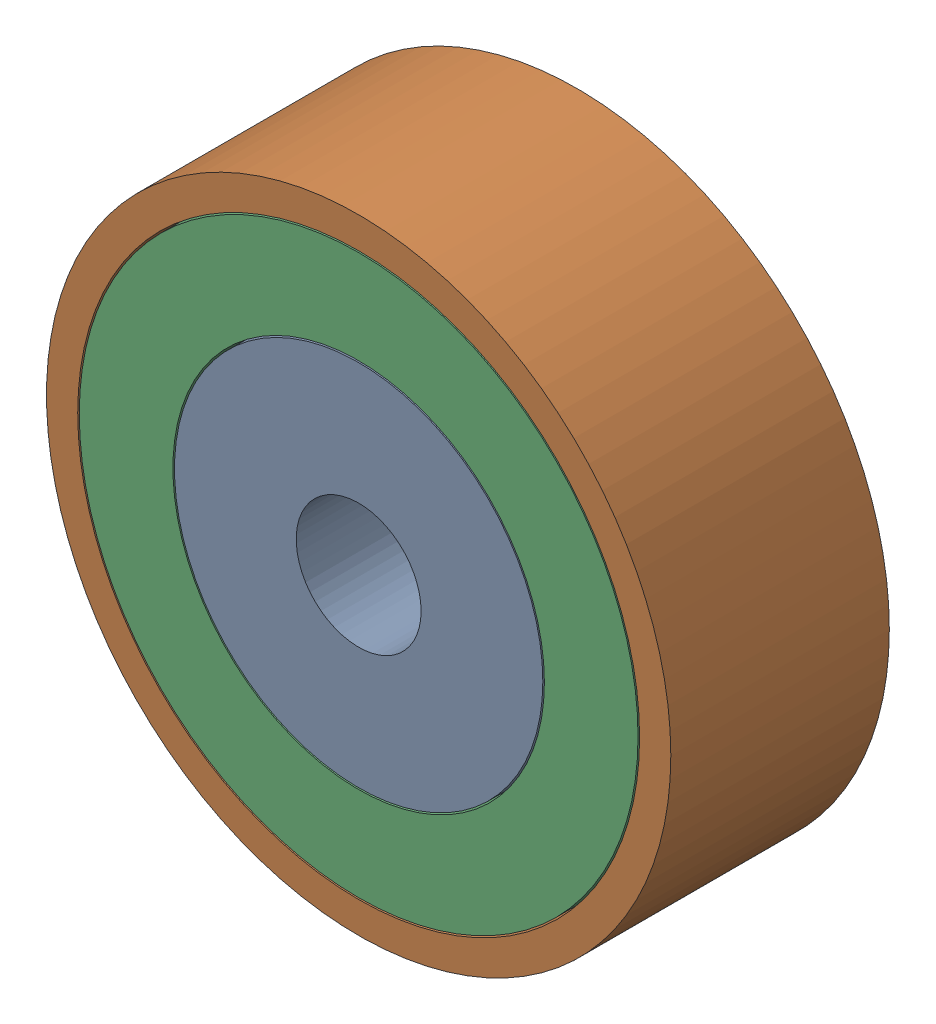
SolidWorks assembly 镜向轴承10, configuration 默认. Lengths in mm.
Overall size (20 20 7).
3 component instances, 3 part files, 4 mates.
Components (placement in the parent):
- 镜向轴承内圈-1: 镜向轴承内圈 [默认] at (-5.0655 0.8032 -6.5) size (11.8 11.8 7)
- 镜向轴承外圈-1: 镜向轴承外圈 [默认] at (-5.0655 0.8032 -6.5) size (20 20 7)
- 镜向轴承中圈-1: 镜向轴承中圈 [默认] at (-5.0655 0.8032 -6.5) size (17.9 17.9 7)
Mates (geometry in assembly coordinates):
- 重合1: coincident: plane of ? through (-5.0655 0.8032 -13.5) normal (0 0 -1); plane of ? through (-5.0655 0.8032 -13.5) normal (0 0 -1)
- 重合2: coincident: plane of ? through (-5.0655 0.8032 -13.5) normal (0 0 -1); plane of ? through (-5.0655 0.8032 -13.5) normal (0 0 -1)
- 同心1: concentric: cylinder of ? through (-5.0655 0.8032 -13.5) axis (0 0 1) radius 9; cylinder of ? through (-5.0655 0.8032 -13.5) axis (0 0 1) radius 8.95
- 同心2: concentric: cylinder of ? through (-5.0655 0.8032 -13.5) axis (0 0 1) radius 5.9; cylinder of ? through (-5.0655 0.8032 -13.5) axis (0 0 1) radius 5.95
